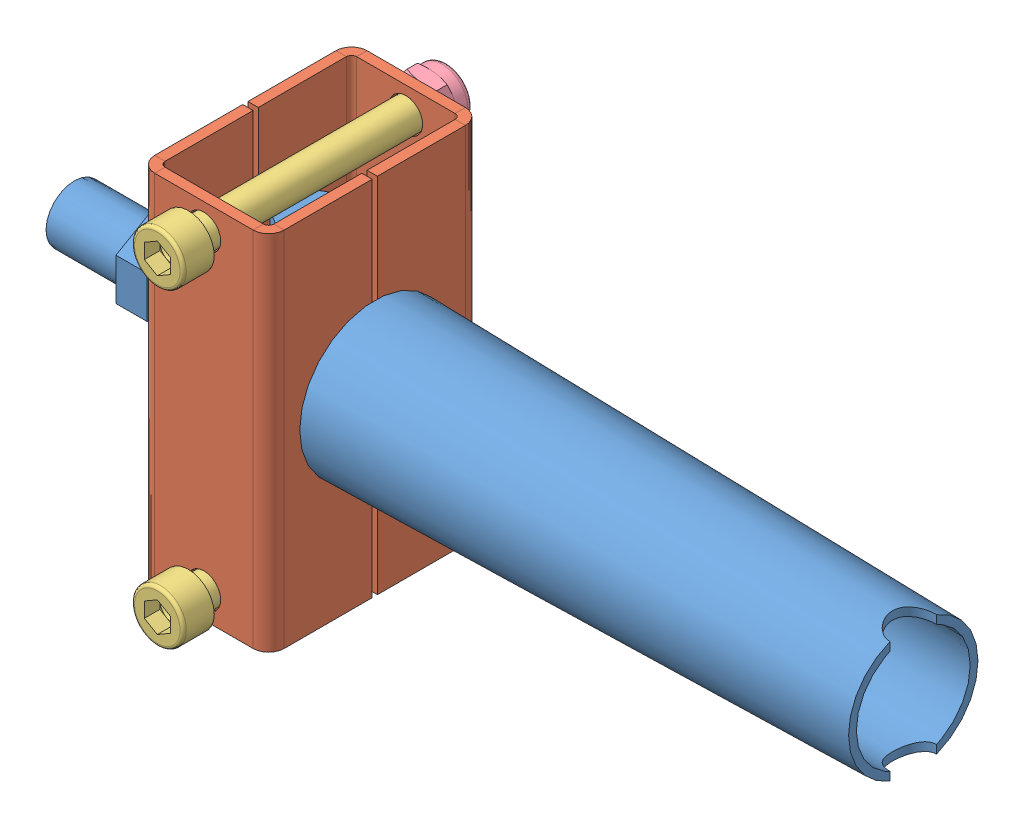
SolidWorks assembly Foam Nozzle Cluster Assembly, configuration Default. Lengths in mm.
Overall size (162.22 74.5 56).
7 component instances, 4 part files, 16 mates.
Components (placement in the parent):
- foam nozzle-1: foam nozzle [Default] at origin size (162.22 46 29)
- foam-nozzle clamp-1: foam-nozzle clamp [Default] at (45.5 -35 -20.5) x (0 1 0) z (1 0 0) size (70 20 25)
- foam-nozzle clamp-2: foam-nozzle clamp [Default] at (45.5 35 20.5) x (0 -1 0) z (1 0 0) size (70 20 25)
- socket head cap screw_din-1: socket head cap screw_din [DIN 912 M6 x 50 --- 24N] at (45.5 30 29.5) x (0 0 -1) z (1 0 0) size (56 10 10)
- socket head cap screw_din-2: socket head cap screw_din [DIN 912 M6 x 50 --- 24N] at (45.5 -30 29.5) x (0 0 -1) z (1 0 0) size (56 10 10)
- prevailing torque nut thin insert_din-1: prevailing torque nut thin insert_din [DIN EN ISO 10511 - M6 - N] at (45.5 30 -23.4) x (0.923728 0.383049 0) z (0 0 -1) size (10 11.55 6)
- prevailing torque nut thin insert_din-2: prevailing torque nut thin insert_din [DIN EN ISO 10511 - M6 - N] at (45.5 -30 -23.4) x (0.923728 0.383049 0) z (0 0 -1) size (10 11.55 6)
Mates (geometry in assembly coordinates):
- Coincident1: coordinate: point of bec phun bot - v2-1
- Coincident2: coincident anti-aligned: plane of bec phun bot - v2-1 through (58 9 0) normal (-1 0 0); plane of kep bec phun bot-1 through (58 35 -20.5) normal (1 0 0)
- Coincident4: coincident anti-aligned: plane of bec phun bot - v2-1 through (58 9 0) normal (-1 0 0); plane of kep bec phun bot-1 through (58 35 -20.5) normal (1 0 0)
- Coincident5: coincident anti-aligned: plane of bec phun bot - v2-1 through (38 0 -11.547) normal (0 -0.5 -0.866025); plane of kep bec phun bot-1 through (32.999 -10 -5.7735) normal (0 0.5 0.866025)
- Coincident6: coincident anti-aligned: plane of bec phun bot - v2-1 through (38 10 -5.7735) normal (0 0.5 -0.866025); plane of kep bec phun bot-1 through (32.999 0 -11.547) normal (0 -0.5 0.866025)
- Coincident7: coincident anti-aligned: plane of bec phun bot - v2-1 through (38 -10 5.7735) normal (0 -0.5 0.866025); plane of kep bec phun bot-2 through (32.999 0 11.547) normal (0 0.5 -0.866025)
- Coincident8: coincident anti-aligned: plane of bec phun bot - v2-1 through (38 0 11.547) normal (0 0.5 0.866025); plane of kep bec phun bot-2 through (32.999 10 5.7735) normal (0 -0.5 -0.866025)
- Coincident9: coincident anti-aligned: plane of bec phun bot - v2-1 through (58 9 0) normal (-1 0 0); plane of kep bec phun bot-2 through (58 -35 20.5) normal (1 0 0)
- Concentric5: concentric aligned: cylinder of kep bec phun bot-2 through (45.5 30 0.499) axis (0 0 1) radius 3.25; cylinder of socket head cap screw_din-1 through (45.5 30 61.25) axis (0 0 1) radius 5
- Distance2: distance = 3 mm anti-aligned: plane of kep bec phun bot-2 through (58 -35 20.5) normal (0 0 1); plane of socket head cap screw_din-1 through (45.5 35 23.5) normal (0 0 -1)
- Concentric6: concentric aligned: cylinder of kep bec phun bot-2 through (45.5 -30 0.499) axis (0 0 1) radius 3.25; cylinder of socket head cap screw_din-2 through (45.5 -30 61.25) axis (0 0 1) radius 5
- Distance1: distance = 3 mm anti-aligned: plane of kep bec phun bot-2 through (58 -35 20.5) normal (0 0 1); plane of socket head cap screw_din-2 through (45.5 -25 23.5) normal (0 0 -1)
- Concentric7: concentric aligned: cylinder of kep bec phun bot-1 through (45.5 30 -0.499) axis (0 0 -1) radius 3.25; cylinder of prevailing torque nut thin insert_din-1 through (45.5 30 -42.45) axis (0 0 -1) radius 3
- Coincident12: coincident anti-aligned: plane of kep bec phun bot-1 through (58 35 -20.5) normal (0 0 -1); plane of prevailing torque nut thin insert_din-1 through (36.2627 26.1695 -20.5) normal (0 0 1)
- Concentric8: concentric aligned: cylinder of kep bec phun bot-1 through (45.5 -30 -0.499) axis (0 0 -1) radius 3.25; cylinder of prevailing torque nut thin insert_din-2 through (45.5 -30 -42.45) axis (0 0 -1) radius 3
- Coincident13: coincident anti-aligned: plane of kep bec phun bot-1 through (58 35 -20.5) normal (0 0 -1); plane of prevailing torque nut thin insert_din-2 through (36.2627 -33.8305 -20.5) normal (0 0 1)
